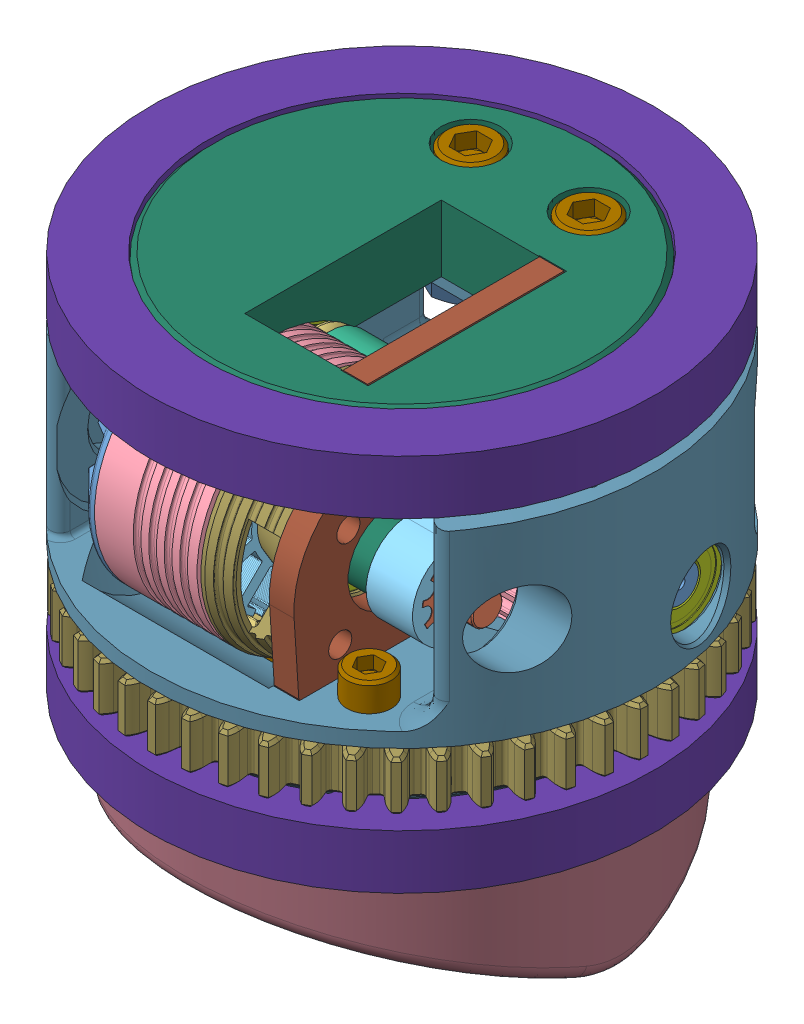
SolidWorks assembly Teathered Swerve Assem, configuration Default. Lengths in mm.
Overall size (65 79.59 67.05).
128 component instances, 35 part files, 78 mates.
Components (placement in the parent):
- Teathered Swerve Inner Structure-1: Teathered Swerve Inner Structure [Default] at origin
- BA-2310-Motor.STEP-1: BA-2310-Motor.STEP [Default] at (13.218 51.7723 56.3355) x (0 0.707107 0.707107) z (-1 0 0) size (29.1 29.1 46)
  - 2310-Rotor-Assem.STEP-1: 2310-Rotor-Assem.STEP [Default] at (14.7295 2.66 3.5453) size (29.1 29.1 46)
    - 23mm-Endbell.STEP-1: 23mm-Endbell.STEP [Default] at (-57.7218 14.2616 14.8949) size (29.1 29.1 12.75)
    - 2310-Shaft.STEP-1: 2310-Shaft.STEP [Default] at (-57.7218 14.2616 -15.3551) size (4 4 46)
    - 2310-Magnet.STEP-1: 2310-Magnet.STEP [Default] at (-57.7218 14.2616 8.6449) size (4 1.65 10)
    - 2310-Magnet.STEP-2: 2310-Magnet.STEP [Default] at (-57.7218 14.2616 8.6449) x (0.900969 0.433884 0) z (0 0 1) size (4 1.65 10)
    - 2310-Magnet.STEP-3: 2310-Magnet.STEP [Default] at (-57.7218 14.2616 8.6449) x (0.62349 0.781831 0) z (0 0 1) size (4 1.65 10)
    - 2310-Magnet.STEP-4: 2310-Magnet.STEP [Default] at (-57.7218 14.2616 8.6449) x (0.222521 0.974928 0) z (0 0 1) size (4 1.65 10)
    - 2310-Magnet.STEP-5: 2310-Magnet.STEP [Default] at (-57.7218 14.2616 8.6449) x (-0.222521 0.974928 0) z (0 0 1) size (4 1.65 10)
    - 2310-Magnet.STEP-6: 2310-Magnet.STEP [Default] at (-57.7218 14.2616 8.6449) x (-0.62349 0.781831 0) z (0 0 1) size (4 1.65 10)
    - 2310-Magnet.STEP-7: 2310-Magnet.STEP [Default] at (-57.7218 14.2616 8.6449) x (-0.900969 0.433884 0) z (0 0 1) size (4 1.65 10)
    - 2310-Magnet.STEP-8: 2310-Magnet.STEP [Default] at (-57.7218 14.2616 8.6449) x (-1 0 0) z (0 0 1) size (4 1.65 10)
    - 2310-Magnet.STEP-9: 2310-Magnet.STEP [Default] at (-57.7218 14.2616 8.6449) x (-0.900969 -0.433884 0) z (0 0 1) size (4 1.65 10)
    - 2310-Magnet.STEP-10: 2310-Magnet.STEP [Default] at (-57.7218 14.2616 8.6449) x (-0.62349 -0.781831 0) z (0 0 1) size (4 1.65 10)
    - 2310-Magnet.STEP-11: 2310-Magnet.STEP [Default] at (-57.7218 14.2616 8.6449) x (-0.222521 -0.974928 0) z (0 0 1) size (4 1.65 10)
    - 2310-Magnet.STEP-12: 2310-Magnet.STEP [Default] at (-57.7218 14.2616 8.6449) x (0.222521 -0.974928 0) z (0 0 1) size (4 1.65 10)
    - 2310-Magnet.STEP-13: 2310-Magnet.STEP [Default] at (-57.7218 14.2616 8.6449) x (0.62349 -0.781831 0) z (0 0 1) size (4 1.65 10)
    - 2310-Magnet.STEP-14: 2310-Magnet.STEP [Default] at (-57.7218 14.2616 8.6449) x (0.900969 -0.433884 0) z (0 0 1) size (4 1.65 10)
    - 2310-Fluxring.STEP-1: 2310-Fluxring.STEP [Default] at (-57.7218 14.2616 7.6449) size (29.1 29.1 13.25)
  - 2310-Stator-Assem.STEP-1: 2310-Stator-Assem.STEP [Default] at (-38.1007 -3.4232 24.6837) size (29.1 29.1 19.5)
    - 23x10x10mm-Stator.STEP-1: 23x10x10mm-Stator.STEP [Default] at (52.3253 8.3812 -27.0554) size (23 23 10)
      - 23x10x5mm-Stator.STEP-1: 23x10x5mm-Stator.STEP [Default] at (-16.2466 9.1923 4.328) size (23 23 5)
        - 23x10x1mm-Stator.STEP-1: 23x10x1mm-Stator.STEP [Default] at (-15.1244 2.7036 6.5442) size (23 23 1)
          - 23x10-Stator-Plate.STEP-1: 23x10-Stator-Plate.STEP [Default] at (-25.8459 0.0676 13.4926) size (23 23 0.2)
          - 23x10-Stator-Plate.STEP-2: 23x10-Stator-Plate.STEP [Default] at (-25.8459 0.0676 13.2926) size (23 23 0.2)
          - 23x10-Stator-Plate.STEP-3: 23x10-Stator-Plate.STEP [Default] at (-25.8459 0.0676 13.0926) size (23 23 0.2)
          - 23x10-Stator-Plate.STEP-4: 23x10-Stator-Plate.STEP [Default] at (-25.8459 0.0676 12.8926) size (23 23 0.2)
          - 23x10-Stator-Plate.STEP-5: 23x10-Stator-Plate.STEP [Default] at (-25.8459 0.0676 12.6926) size (23 23 0.2)
        - 23x10x1mm-Stator.STEP-2: 23x10x1mm-Stator.STEP [Default] at (-15.1244 2.7036 5.5442) size (23 23 1)
          - 23x10-Stator-Plate.STEP-1: 23x10-Stator-Plate.STEP [Default] at (-25.8459 0.0676 13.4926) size (23 23 0.2)
          - 23x10-Stator-Plate.STEP-2: 23x10-Stator-Plate.STEP [Default] at (-25.8459 0.0676 13.2926) size (23 23 0.2)
          - 23x10-Stator-Plate.STEP-3: 23x10-Stator-Plate.STEP [Default] at (-25.8459 0.0676 13.0926) size (23 23 0.2)
          - 23x10-Stator-Plate.STEP-4: 23x10-Stator-Plate.STEP [Default] at (-25.8459 0.0676 12.8926) size (23 23 0.2)
          - 23x10-Stator-Plate.STEP-5: 23x10-Stator-Plate.STEP [Default] at (-25.8459 0.0676 12.6926) size (23 23 0.2)
        - 23x10x1mm-Stator.STEP-3: 23x10x1mm-Stator.STEP [Default] at (-15.1244 2.7036 4.5442) size (23 23 1)
          - 23x10-Stator-Plate.STEP-1: 23x10-Stator-Plate.STEP [Default] at (-25.8459 0.0676 13.4926) size (23 23 0.2)
          - 23x10-Stator-Plate.STEP-2: 23x10-Stator-Plate.STEP [Default] at (-25.8459 0.0676 13.2926) size (23 23 0.2)
          - 23x10-Stator-Plate.STEP-3: 23x10-Stator-Plate.STEP [Default] at (-25.8459 0.0676 13.0926) size (23 23 0.2)
          - 23x10-Stator-Plate.STEP-4: 23x10-Stator-Plate.STEP [Default] at (-25.8459 0.0676 12.8926) size (23 23 0.2)
          - 23x10-Stator-Plate.STEP-5: 23x10-Stator-Plate.STEP [Default] at (-25.8459 0.0676 12.6926) size (23 23 0.2)
        - 23x10x1mm-Stator.STEP-4: 23x10x1mm-Stator.STEP [Default] at (-15.1244 2.7036 3.5442) size (23 23 1)
          - 23x10-Stator-Plate.STEP-1: 23x10-Stator-Plate.STEP [Default] at (-25.8459 0.0676 13.4926) size (23 23 0.2)
          - 23x10-Stator-Plate.STEP-2: 23x10-Stator-Plate.STEP [Default] at (-25.8459 0.0676 13.2926) size (23 23 0.2)
          - 23x10-Stator-Plate.STEP-3: 23x10-Stator-Plate.STEP [Default] at (-25.8459 0.0676 13.0926) size (23 23 0.2)
          - 23x10-Stator-Plate.STEP-4: 23x10-Stator-Plate.STEP [Default] at (-25.8459 0.0676 12.8926) size (23 23 0.2)
          - 23x10-Stator-Plate.STEP-5: 23x10-Stator-Plate.STEP [Default] at (-25.8459 0.0676 12.6926) size (23 23 0.2)
        - 23x10x1mm-Stator.STEP-5: 23x10x1mm-Stator.STEP [Default] at (-15.1244 2.7036 2.5442) size (23 23 1)
          - 23x10-Stator-Plate.STEP-1: 23x10-Stator-Plate.STEP [Default] at (-25.8459 0.0676 13.4926) size (23 23 0.2)
          - 23x10-Stator-Plate.STEP-2: 23x10-Stator-Plate.STEP [Default] at (-25.8459 0.0676 13.2926) size (23 23 0.2)
          - 23x10-Stator-Plate.STEP-3: 23x10-Stator-Plate.STEP [Default] at (-25.8459 0.0676 13.0926) size (23 23 0.2)
          - 23x10-Stator-Plate.STEP-4: 23x10-Stator-Plate.STEP [Default] at (-25.8459 0.0676 12.8926) size (23 23 0.2)
          - 23x10-Stator-Plate.STEP-5: 23x10-Stator-Plate.STEP [Default] at (-25.8459 0.0676 12.6926) size (23 23 0.2)
      - 23x10x5mm-Stator.STEP-2: 23x10x5mm-Stator.STEP [Default] at (-16.2466 9.1923 -0.672) size (23 23 5)
        - 23x10x1mm-Stator.STEP-1: 23x10x1mm-Stator.STEP [Default] at (-15.1244 2.7036 6.5442) size (23 23 1)
          - 23x10-Stator-Plate.STEP-1: 23x10-Stator-Plate.STEP [Default] at (-25.8459 0.0676 13.4926) size (23 23 0.2)
          - 23x10-Stator-Plate.STEP-2: 23x10-Stator-Plate.STEP [Default] at (-25.8459 0.0676 13.2926) size (23 23 0.2)
          - 23x10-Stator-Plate.STEP-3: 23x10-Stator-Plate.STEP [Default] at (-25.8459 0.0676 13.0926) size (23 23 0.2)
          - 23x10-Stator-Plate.STEP-4: 23x10-Stator-Plate.STEP [Default] at (-25.8459 0.0676 12.8926) size (23 23 0.2)
          - 23x10-Stator-Plate.STEP-5: 23x10-Stator-Plate.STEP [Default] at (-25.8459 0.0676 12.6926) size (23 23 0.2)
        - 23x10x1mm-Stator.STEP-2: 23x10x1mm-Stator.STEP [Default] at (-15.1244 2.7036 5.5442) size (23 23 1)
          - 23x10-Stator-Plate.STEP-1: 23x10-Stator-Plate.STEP [Default] at (-25.8459 0.0676 13.4926) size (23 23 0.2)
          - 23x10-Stator-Plate.STEP-2: 23x10-Stator-Plate.STEP [Default] at (-25.8459 0.0676 13.2926) size (23 23 0.2)
          - 23x10-Stator-Plate.STEP-3: 23x10-Stator-Plate.STEP [Default] at (-25.8459 0.0676 13.0926) size (23 23 0.2)
          - 23x10-Stator-Plate.STEP-4: 23x10-Stator-Plate.STEP [Default] at (-25.8459 0.0676 12.8926) size (23 23 0.2)
          - 23x10-Stator-Plate.STEP-5: 23x10-Stator-Plate.STEP [Default] at (-25.8459 0.0676 12.6926) size (23 23 0.2)
        - 23x10x1mm-Stator.STEP-3: 23x10x1mm-Stator.STEP [Default] at (-15.1244 2.7036 4.5442) size (23 23 1)
          - 23x10-Stator-Plate.STEP-1: 23x10-Stator-Plate.STEP [Default] at (-25.8459 0.0676 13.4926) size (23 23 0.2)
          - 23x10-Stator-Plate.STEP-2: 23x10-Stator-Plate.STEP [Default] at (-25.8459 0.0676 13.2926) size (23 23 0.2)
          - 23x10-Stator-Plate.STEP-3: 23x10-Stator-Plate.STEP [Default] at (-25.8459 0.0676 13.0926) size (23 23 0.2)
          - 23x10-Stator-Plate.STEP-4: 23x10-Stator-Plate.STEP [Default] at (-25.8459 0.0676 12.8926) size (23 23 0.2)
          - 23x10-Stator-Plate.STEP-5: 23x10-Stator-Plate.STEP [Default] at (-25.8459 0.0676 12.6926) size (23 23 0.2)
        - 23x10x1mm-Stator.STEP-4: 23x10x1mm-Stator.STEP [Default] at (-15.1244 2.7036 3.5442) size (23 23 1)
          - 23x10-Stator-Plate.STEP-1: 23x10-Stator-Plate.STEP [Default] at (-25.8459 0.0676 13.4926) size (23 23 0.2)
          - 23x10-Stator-Plate.STEP-2: 23x10-Stator-Plate.STEP [Default] at (-25.8459 0.0676 13.2926) size (23 23 0.2)
          - 23x10-Stator-Plate.STEP-3: 23x10-Stator-Plate.STEP [Default] at (-25.8459 0.0676 13.0926) size (23 23 0.2)
          - 23x10-Stator-Plate.STEP-4: 23x10-Stator-Plate.STEP [Default] at (-25.8459 0.0676 12.8926) size (23 23 0.2)
          - 23x10-Stator-Plate.STEP-5: 23x10-Stator-Plate.STEP [Default] at (-25.8459 0.0676 12.6926) size (23 23 0.2)
        - 23x10x1mm-Stator.STEP-5: 23x10x1mm-Stator.STEP [Default] at (-15.1244 2.7036 2.5442) size (23 23 1)
          - 23x10-Stator-Plate.STEP-1: 23x10-Stator-Plate.STEP [Default] at (-25.8459 0.0676 13.4926) size (23 23 0.2)
          - 23x10-Stator-Plate.STEP-2: 23x10-Stator-Plate.STEP [Default] at (-25.8459 0.0676 13.2926) size (23 23 0.2)
          - 23x10-Stator-Plate.STEP-3: 23x10-Stator-Plate.STEP [Default] at (-25.8459 0.0676 13.0926) size (23 23 0.2)
          - 23x10-Stator-Plate.STEP-4: 23x10-Stator-Plate.STEP [Default] at (-25.8459 0.0676 12.8926) size (23 23 0.2)
          - 23x10-Stator-Plate.STEP-5: 23x10-Stator-Plate.STEP [Default] at (-25.8459 0.0676 12.6926) size (23 23 0.2)
    - 4x11x4-BRG.STEP-1: 4x11x4-BRG.STEP [Default] at (-4.8916 20.3447 -18.4846) x (0 0 1) z (-0.998854 -0.047866 0) size (3.99 11 11)
      - 694HZZ_SOLID_1-1.STEP-1: 694HZZ_SOLID_1-1.STEP [Default] at origin size (3.99 6.18 6.18)
      - 694HZZ_SOLID_2-1.STEP-1: 694HZZ_SOLID_2-1.STEP [Default] at origin size (3.99 11 11)
      - 694HZZ_SOLID_3-1.STEP-1: 694HZZ_SOLID_3-1.STEP [Default] at origin size (2.34 9.37 9.37)
    - 4x8x3-BRG.STEP-1: 4x8x3-BRG.STEP [Default] at (-4.8916 20.3447 -2.9921) x (0 0 -1) z (0.838857 -0.544351 0) size (3 8 8)
      - SMR84ZZ_SOLID_1.STEP-1: SMR84ZZ_SOLID_1.STEP [Default] at origin size (3 5.01 5.01)
      - SMR84ZZ_SOLID_2.STEP-1: SMR84ZZ_SOLID_2.STEP [Default] at origin size (3 8 8)
      - SMR84ZZ_SOLID_3.STEP-1: SMR84ZZ_SOLID_3.STEP [Default] at origin size (1.76 7.4 7.4)
    - 2310-Mount.STEP-1: 2310-Mount.STEP [Default] at (-4.8916 20.3447 -20.9907) size (29.1 29.1 19.5)
  - Spacer-4mm.STEP-1: Spacer-4mm.STEP [Default] at (-42.9923 16.9215 23.1902) size (6 6 0.25)
  - Spacer-4mm.STEP-2: Spacer-4mm.STEP [Default] at (-42.9923 16.9215 3.9552) size (6 6 0.25)
  - C-Clip-4mm_98541A112.STEP-1: C-Clip-4mm_98541A112.STEP [Default] at (-42.9923 16.9215 3.7402) x (0 0 -1) z (0.963178 -0.268866 0) size (0.4 6.8 5.16)
  - Collar-4mm.STEP-1: Collar-4mm.STEP [Default] at (-42.9923 16.9215 -1.4598) x (0 1 0) z (0 0 1) size (8.5 8.5 5)
  - M2.5x3-SetScrew.STEP-1: M2.5x3-SetScrew.STEP [Default] at (-42.9923 20.0215 0.7902) x (0.871933 0 -0.489626) z (0 1 0) size (2.89 2.5 3.01)
- Zoro Bearing 50mmID 65mm OD 7mmWidth-1: Zoro Bearing 50mmID 65mm OD 7mmWidth [Default] at (0 50.475 0) size (65 7 65)
- Zoro Bearing 50mmID 65mm OD 7mmWidth-2: Zoro Bearing 50mmID 65mm OD 7mmWidth [Default] at (0 8.55 0) size (65 7 65)
- Wheel with Pully-1: Wheel with Pully [Default] x (0 -0.449614 0.893223) z (0 -0.893223 -0.449614) size (38.1 24.77 38.1)
- Inner Modual Intermediate Shaft-1: Inner Modual Intermediate Shaft [Default] at (1.7272 27.4182 -7.2941) x (0 -0.995575 -0.093965) z (0 -0.093965 0.995575) size (5.5 53.85 4.76)
- Drive Stage 1 Pinion-1: Drive Stage 1 Pinion [Aluminum Version] at (17.8528 33.3375 13.97) x (0 0.98945 0.144875) z (0 0.144875 -0.98945) size (8.79 6.35 8.54)
- Drive Stage 2 Pinion-1: Drive Stage 2 Pinion [Default] at (-12.1285 27.4182 -7.2941) x (0 -0.995575 -0.093965) z (0 -0.093965 0.995575) size (10.57 36.37 10.57)
- Drive Stage 1 Pully-1: Drive Stage 1 Pully [Default] at (17.9578 27.4182 -7.2941) x (0 -0.995575 -0.093965) z (0 -0.093965 0.995575) size (24.89 10.48 24.89)
- Drive Stage 1 Belt-1: Drive Stage 1 Belt [Default] at (17.9578 33.3375 13.97) x (1 0 0) z (0 0.268176 0.96337) size (6 27.13 41.27)
- Drive Stage 2 Belt-1: Drive Stage 2 Belt [Default] at (-12.1285 27.4182 -7.2941) x (1 0 0) z (0 0.966388 -0.257089) size (9 31.9 49.96)
- 60355K861_Ball Bearing-1: 60355K861_Ball Bearing [60355K861] at (26.162 27.4182 -7.2941) x (0 0 -1) z (1 0 0) size (12.7 12.7 4.98)
- 60355K861_Ball Bearing-2: 60355K861_Ball Bearing [60355K861] at (-22.7838 27.4182 -7.2941) x (0 0.531717 -0.846922) z (1 0 0) size (12.7 12.7 4.98)
- Wheel Shaft-1: Wheel Shaft [Default] x (0 0 1) z (1 0 0) size (9.53 10.25 47.62)
- socket head cap screw_ai-4: socket head cap screw_ai [HX-SHCS 0.164-32x0.375x0.375-N] at (23.2156 17.13 10.795) x (-1 0 0) z (0 0.924225 0.381849) size (13.69 6.86 6.86)
- socket head cap screw_ai-7: socket head cap screw_ai [HX-SHCS 0.164-32x0.375x0.375-N] at (23.2156 49.53 5.715) x (-1 0 0) z (0 0.924225 0.381849) size (13.69 6.86 6.86)
- socket head cap screw_ai-8: socket head cap screw_ai [HX-SHCS 0.164-32x0.375x0.375-N] at (23.2156 49.53 -1.905) x (-1 0 0) z (0 0.924225 0.381849) size (13.69 6.86 6.86)
- socket head cap screw_ai-10: socket head cap screw_ai [HX-SHCS 0.138-32x0.375x0.375-N] at (16.8402 26.6677 21.0887) x (0 -1 0) z (0 0 1) size (13.03 5.74 5.74)
- socket head cap screw_ai-11: socket head cap screw_ai [HX-SHCS 0.138-32x0.375x0.375-N] at (8.255 26.6677 -25.694) x (0 -1 0) z (0 0 1) size (13.03 5.74 5.74)
- socket head cap screw_ai-12: socket head cap screw_ai [HX-SHCS 0.138-32x0.375x0.375-N] at (-15.24 26.6677 -22.2726) x (0 -1 0) z (0 0 1) size (13.03 5.74 5.74)
- socket head cap screw_ai-13: socket head cap screw_ai [HX-SHCS 0.138-32x0.375x0.375-N] at (-26.2298 26.6677 6.35) x (0 -1 0) z (0 0 1) size (13.03 5.74 5.74)
- machine screw nut hex_ai-6: machine screw nut hex_ai [MSHXNUT 0.164-32-S-N] at (-7.62 38.9105 -16.51) x (1 0 0) z (0 -1 0) size (8.74 10.09 3.3)
- machine screw nut hex_ai-7: machine screw nut hex_ai [MSHXNUT 0.164-32-S-N] at (7.62 38.9105 -16.51) x (1 0 0) z (0 -1 0) size (8.74 10.09 3.3)
- socket head cap screw_ai-16: socket head cap screw_ai [HX-SHCS 0.164-32x0.5x0.5-N] at (7.62 53.975 -16.51) x (0 -1 0) z (0 0 1) size (16.87 6.86 6.86)
- socket head cap screw_ai-17: socket head cap screw_ai [HX-SHCS 0.164-32x0.5x0.5-N] at (-7.62 53.975 -16.51) x (0 -1 0) z (0 0 1) size (16.87 6.86 6.86)
- Drive Motor Mount-1: Drive Motor Mount [Default] at origin size (3.17 41.93 34.92)
- Final Steer Gear-1: Final Steer Gear [Default] at origin size (64.76 6.35 64.73)
- Inner Structure Bottom-1: Inner Structure Bottom [Default] at origin size (56.35 17.75 56.35)
- Inner Structure Mid-1: Inner Structure Mid [Default] at origin size (65 46.99 65)
- Inner Structure Top-1: Inner Structure Top [Default] at origin size (56.52 8.59 56.35)
- .375 Thunder Hex Bearing-2: .375 Thunder Hex Bearing [Default] at (-18.4023 0 0) x (1 0 0) z (0 -0.11391 0.993491) size (7.11 24.61 24.61)
- .375 Thunder Hex Bearing-3: .375 Thunder Hex Bearing [Default] at (6.3373 0 0) x (-1 0 0) z (0 -0.999894 -0.014533) size (7.11 24.61 24.61)
Mates (geometry in assembly coordinates):
- Coincident1: coincident aligned: plane of Teathered Swerve Inner Structure-1 through (0 0 0) normal (0 0 1)
- Coincident2: coincident aligned: plane of Teathered Swerve Inner Structure-1 through (0 0 0) normal (0 1 0)
- Coincident3: coincident aligned: plane of Teathered Swerve Inner Structure-1 through (0 0 0) normal (1 0 0)
- Concentric1: concentric aligned: circle of Teathered Swerve Sketch-1; cylinder of BA-2310-Motor.STEP-1/2310-Rotor-Assem.STEP-1/2310-Shaft.STEP-1 through (-20.9722 33.3375 13.97) axis (1 0 0) radius 2
- Coincident4: coincident: line of Teathered Swerve Inner Structure-1 through (9.525 0 28.5242) axis (0 0 -1); plane of BA-2310-Motor.STEP-1/2310-Stator-Assem.STEP-1/2310-Mount.STEP-1 through (9.525 33.3375 13.97) normal (1 0 0)
- Coincident5: coincident anti-aligned: circle of Teathered Swerve Sketch-1; cylinder of Zoro Bearing 50mmID 65mm OD 7mmWidth-2 through (0 12.05 0) axis (0 -1 0) radius 25
- Concentric2: concentric aligned: cylinder of Zoro Bearing 50mmID 65mm OD 7mmWidth-1 through (0 53.975 0) axis (0 -1 0) radius 25; cylinder of Zoro Bearing 50mmID 65mm OD 7mmWidth-2 through (0 12.05 0) axis (0 -1 0) radius 25
- Coincident6: coincident: line of Teathered Swerve Inner Structure-1 through (0 53.975 -32.5) axis (0 0 1); plane of Zoro Bearing 50mmID 65mm OD 7mmWidth-1 through (0 53.975 0) normal (0 1 0)
- Coincident7: coincident: line of Teathered Swerve Inner Structure-1 through (0 5.05 -32.5) axis (0 0 1); plane of Zoro Bearing 50mmID 65mm OD 7mmWidth-2 through (0 5.05 0) normal (0 -1 0)
- Coincident8: coincident anti-aligned: plane of Wheel with Pully-1 through (0 0 0) normal (-1 0 0)
- Coincident9: coincident anti-aligned: circle of Teathered Swerve Sketch-1; cylinder of Wheel with Pully-1 through (6.35 0 0) axis (-1 0 0) radius 19.05
- Concentric3: concentric anti-aligned: circle of Teathered Swerve Sketch-1; cylinder of Inner Modual Intermediate Shaft-1 through (23.6728 27.4182 -7.2941) axis (-1 0 0) radius 0.635
- Concentric4: concentric anti-aligned: cylinder of BA-2310-Motor.STEP-1/2310-Rotor-Assem.STEP-1/2310-Shaft.STEP-1 through (-20.9722 33.3375 13.97) axis (1 0 0) radius 2; cylinder of Drive Stage 1 Pinion-1 through (22.3613 33.3375 13.97) axis (-1 0 0) radius 2
- Concentric5: concentric anti-aligned: cylinder of Inner Modual Intermediate Shaft-1 through (23.6728 27.4182 -7.2941) axis (-1 0 0) radius 0.635; cylinder of Drive Stage 2 Pinion-1 through (-3.3973 27.4182 -7.2941) axis (1 0 0) radius 5.2826
- Coincident12: coincident aligned: plane of Wheel with Pully-1 through (-17.4625 0 0) normal (1 0 0); plane of Drive Stage 2 Pinion-1 through (-17.4625 27.4182 -7.2941) normal (1 0 0)
- Concentric6: concentric aligned: cylinder of Inner Modual Intermediate Shaft-1 through (23.6728 27.4182 -7.2941) axis (-1 0 0) radius 0.635; cylinder of Drive Stage 1 Pully-1 through (23.6728 27.4182 -7.2941) axis (-1 0 0) radius 3.81
- Width1: width anti-aligned: plane of Drive Stage 1 Belt-1 through (14.9578 33.3375 13.97) normal (-1 0 0); plane of Drive Stage 1 Pully-1 through (20.9578 33.3375 13.97) normal (1 0 0); plane of Drive Stage 1 Belt-1 through (14.4653 27.4182 -7.2941) normal (1 0 0); plane of Drive Stage 1 Pully-1 through (21.4503 27.4182 -7.2941) normal (-1 0 0)
- Concentric7: concentric anti-aligned: cylinder of BA-2310-Motor.STEP-1/2310-Rotor-Assem.STEP-1/2310-Shaft.STEP-1 through (-20.9722 33.3375 13.97) axis (1 0 0) radius 2; cylinder of Drive Stage 1 Belt-1 through (20.9578 33.3375 13.97) axis (-1 0 0) radius 2.4638
- Concentric8: concentric aligned: cylinder of Drive Stage 1 Pully-1 through (23.6728 27.4182 -7.2941) axis (-1 0 0) radius 3.81; cylinder of Drive Stage 1 Belt-1 through (20.9578 27.4182 -7.2941) axis (-1 0 0) radius 10.3886
- Width2: width anti-aligned: plane of Drive Stage 2 Belt-1 through (-16.6285 27.4182 -7.2941) normal (-1 0 0); plane of Drive Stage 2 Pinion-1 through (-7.6285 27.4182 -7.2941) normal (1 0 0); plane of Drive Stage 2 Belt-1 through (-17.4625 27.4182 -7.2941) normal (1 0 0); plane of Drive Stage 2 Pinion-1 through (-6.7945 27.4182 -7.2941) normal (-1 0 0)
- Concentric9: concentric aligned: cylinder of Inner Modual Intermediate Shaft-1 through (23.6728 27.4182 -7.2941) axis (-1 0 0) radius 0.635; cylinder of Drive Stage 2 Belt-1 through (-7.6285 27.4182 -7.2941) axis (-1 0 0) radius 2.4638
- Concentric10: concentric aligned: cylinder of Wheel with Pully-1 through (-21.1137 0 0) axis (-1 0 0) radius 15.7209; cylinder of Drive Stage 2 Belt-1 through (-7.6285 0 0) axis (-1 0 0) radius 12.7762
- Coincident14: coincident aligned: plane of Inner Modual Intermediate Shaft-1 through (23.6728 27.4182 -7.2941) normal (1 0 0); plane of Drive Stage 1 Pully-1 through (23.6728 27.4182 -7.2941) normal (1 0 0)
- Parallel1: parallel anti-aligned: plane of Inner Modual Intermediate Shaft-1 through (23.6728 29.0106 -9.5356) normal (0 0.909176 -0.416411); plane of Drive Stage 1 Pully-1 through (22.7203 30.1994 -7.0316) normal (0 -0.909176 0.416411)
- Parallel2: parallel anti-aligned: plane of Inner Modual Intermediate Shaft-1 through (23.6728 30.1556 -7.0357) normal (0 0.815211 0.579164); plane of Drive Stage 2 Pinion-1 through (-5.7785 28.5815 -4.7542) normal (0 -0.815211 -0.579164)
- GearMate1: gear = 63.5 : 25.4 mm: circle of Drive Stage 1 Pinion-1; cylinder of Drive Stage 1 Pully-1 through (23.6728 27.4182 -7.2941) axis (-1 0 0) radius 3.81
- GearMate2: gear = 31.4419 : 25.4 mm: circle of Drive Stage 2 Pinion-1; cylinder of Wheel with Pully-1 through (-21.1137 0 0) axis (-1 0 0) radius 15.7209
- Concentric11: concentric anti-aligned: cylinder of Inner Modual Intermediate Shaft-1 through (28.6512 27.4182 -7.2941) axis (-1 0 0) radius 2.3813; cylinder of 60355K861_Ball Bearing-1 through (28.6512 27.4182 -7.2941) axis (1 0 0) radius 2.3813
- Coincident17: coincident anti-aligned: plane of Drive Stage 1 Pully-1 through (23.6728 27.4182 -7.2941) normal (1 0 0); plane of 60355K861_Ball Bearing-1 through (23.6728 30.0483 -7.2941) normal (-1 0 0)
- Concentric12: concentric aligned: cylinder of Inner Modual Intermediate Shaft-1 through (-25.1968 27.4182 -7.2941) axis (1 0 0) radius 2.3813; cylinder of 60355K861_Ball Bearing-2 through (-20.2946 27.4182 -7.2941) axis (1 0 0) radius 2.3813
- Coincident18: coincident aligned: plane of 60355K861_Ball Bearing-2 through (-25.273 32.5853 -4.05) normal (-1 0 0); plane of Inner Structure Mid-1 through (-25.273 27.4182 -7.2941) normal (-1 0 0)
- Coincident21: coincident aligned: plane of Wheel Shaft-1 through (0 0 0) normal (1 0 0)
- Parallel3: parallel anti-aligned: plane of Wheel Shaft-1 through (23.8125 3.1786 -4.0195) normal (0 0.866025 -0.5); plane of Inner Structure Mid-1 through (-23.8125 2.9329 -5.08) normal (0 -0.866025 0.5)
- Concentric17: concentric anti-aligned: cylinder of Inner Structure Mid-1 through (32.5 17.13 10.795) axis (-1 0 0) radius 2.2479; cylinder of socket head cap screw_ai-4 through (54.9656 17.13 10.795) axis (1 0 0) radius 3.429
- Coincident23: coincident anti-aligned: plane of Inner Structure Mid-1 through (19.05 17.13 10.795) normal (1 0 0); plane of socket head cap screw_ai-4 through (19.05 15.8206 13.9642) normal (-1 0 0)
- Concentric18: concentric anti-aligned: cylinder of Inner Structure Top-1 through (32.5 49.53 5.715) axis (-1 0 0) radius 2.2479; cylinder of socket head cap screw_ai-7 through (54.9656 49.53 5.715) axis (1 0 0) radius 3.429
- Coincident24: coincident anti-aligned: plane of Inner Structure Top-1 through (19.05 49.53 5.715) normal (1 0 0); plane of socket head cap screw_ai-7 through (19.05 48.2206 8.8842) normal (-1 0 0)
- Concentric19: concentric anti-aligned: cylinder of Inner Structure Top-1 through (32.5 49.53 -1.905) axis (-1 0 0) radius 2.2479; cylinder of socket head cap screw_ai-8 through (54.9656 49.53 -1.905) axis (1 0 0) radius 3.429
- Coincident25: coincident anti-aligned: plane of Inner Structure Top-1 through (19.05 49.53 -1.905) normal (1 0 0); plane of socket head cap screw_ai-8 through (19.05 48.2206 1.2642) normal (-1 0 0)
- Concentric20: concentric anti-aligned: cylinder of Drive Motor Mount-1 through (32.501 38.9944 19.6269) axis (-1 0 0) radius 1.5; cylinder of BA-2310-Motor.STEP-1/2310-Stator-Assem.STEP-1/2310-Mount.STEP-1 through (9.525 38.9944 19.6269) axis (1 0 0) radius 1.25
- Concentric21: concentric anti-aligned: cylinder of Inner Structure Mid-1 through (16.8402 53.975 21.0887) axis (0 -1 0) radius 1.7526; cylinder of socket head cap screw_ai-10 through (16.8402 58.4177 21.0887) axis (0 1 0) radius 2.8702
- Coincident26: coincident anti-aligned: plane of Inner Structure Mid-1 through (0 23.1625 0) normal (0 1 0); plane of socket head cap screw_ai-10 through (19.7104 23.1625 21.0887) normal (0 -1 0)
- Concentric22: concentric anti-aligned: cylinder of Inner Structure Mid-1 through (8.255 53.975 -25.694) axis (0 -1 0) radius 1.7526; cylinder of socket head cap screw_ai-11 through (8.255 58.4177 -25.694) axis (0 1 0) radius 2.8702
- Coincident27: coincident anti-aligned: plane of Inner Structure Mid-1 through (0 23.1625 0) normal (0 1 0); plane of socket head cap screw_ai-11 through (11.1252 23.1625 -25.694) normal (0 -1 0)
- Concentric23: concentric anti-aligned: cylinder of Inner Structure Mid-1 through (-15.24 53.975 -22.2726) axis (0 -1 0) radius 1.7526; cylinder of socket head cap screw_ai-12 through (-15.24 58.4177 -22.2726) axis (0 1 0) radius 2.8702
- Coincident28: coincident anti-aligned: plane of Inner Structure Mid-1 through (0 23.1625 0) normal (0 1 0); plane of socket head cap screw_ai-12 through (-12.3698 23.1625 -22.2726) normal (0 -1 0)
- Concentric24: concentric anti-aligned: cylinder of Inner Structure Mid-1 through (-26.2298 53.975 6.35) axis (0 -1 0) radius 1.7526; cylinder of socket head cap screw_ai-13 through (-26.2298 58.4177 6.35) axis (0 1 0) radius 2.8702
- Coincident29: coincident anti-aligned: plane of Inner Structure Mid-1 through (-26.2298 23.1625 6.35) normal (0 1 0); plane of socket head cap screw_ai-13 through (-23.3596 23.1625 6.35) normal (0 -1 0)
- Concentric29: concentric anti-aligned: cylinder of Inner Structure Mid-1 through (-7.62 35.8545 -16.51) axis (0 1 0) radius 2.2479; cylinder of machine screw nut hex_ai-6 through (-7.62 63.948 -16.51) axis (0 -1 0) radius 2.0828
- Coincident33: coincident anti-aligned: plane of Inner Structure Mid-1 through (-18.8486 42.2125 13.0053) normal (0 -1 0); plane of machine screw nut hex_ai-6 through (-16.3576 42.2125 -16.51) normal (0 1 0)
- Concentric30: concentric anti-aligned: cylinder of Inner Structure Mid-1 through (7.62 35.8545 -16.51) axis (0 1 0) radius 2.2479; cylinder of machine screw nut hex_ai-7 through (7.62 63.948 -16.51) axis (0 -1 0) radius 2.0828
- Coincident34: coincident anti-aligned: plane of Inner Structure Mid-1 through (-18.8486 42.2125 13.0053) normal (0 -1 0); plane of machine screw nut hex_ai-7 through (-1.1176 42.2125 -16.51) normal (0 1 0)
- Concentric31: concentric aligned: cylinder of Inner Structure Top-1 through (7.62 35.8545 -16.51) axis (0 1 0) radius 2.2479; cylinder of socket head cap screw_ai-16 through (7.62 85.725 -16.51) axis (0 1 0) radius 3.429
- Coincident35: coincident anti-aligned: plane of Inner Structure Top-1 through (7.62 49.8094 -16.51) normal (0 1 0); plane of socket head cap screw_ai-16 through (11.049 49.8094 -16.51) normal (0 -1 0)
- Concentric32: concentric aligned: cylinder of Inner Structure Top-1 through (-7.62 35.8545 -16.51) axis (0 1 0) radius 2.2479; cylinder of socket head cap screw_ai-17 through (-7.62 85.725 -16.51) axis (0 1 0) radius 3.429
- Coincident36: coincident anti-aligned: plane of Inner Structure Top-1 through (-7.62 49.8094 -16.51) normal (0 1 0); plane of socket head cap screw_ai-17 through (-4.191 49.8094 -16.51) normal (0 -1 0)
- Coincident39: coincident aligned: plane of Drive Motor Mount-1 through (0 0 0) normal (0 0 1)
- Coincident40: coincident aligned: plane of Drive Motor Mount-1 through (0 0 0) normal (0 1 0)
- Coincident41: coincident aligned: plane of Drive Motor Mount-1 through (0 0 0) normal (1 0 0)
- Coincident42: coincident aligned: plane of Final Steer Gear-1 through (0 0 0) normal (0 0 1)
- Coincident43: coincident aligned: plane of Final Steer Gear-1 through (0 0 0) normal (0 1 0)
- Coincident44: coincident aligned: plane of Final Steer Gear-1 through (0 0 0) normal (1 0 0)
- Coincident45: coincident aligned: plane of Inner Structure Bottom-1 through (0 0 0) normal (0 0 1)
- Coincident46: coincident aligned: plane of Inner Structure Bottom-1 through (0 0 0) normal (0 1 0)
- Coincident47: coincident aligned: plane of Inner Structure Bottom-1 through (0 0 0) normal (1 0 0)
- Coincident48: coincident aligned: plane of Inner Structure Mid-1 through (0 0 0) normal (0 0 1)
- Coincident49: coincident aligned: plane of Inner Structure Mid-1 through (0 0 0) normal (0 1 0)
- Coincident50: coincident aligned: plane of Inner Structure Mid-1 through (0 0 0) normal (1 0 0)
- Coincident51: coincident aligned: plane of Inner Structure Top-1 through (0 0 0) normal (0 0 1)
- Coincident52: coincident aligned: plane of Inner Structure Top-1 through (0 0 0) normal (0 1 0)
- Coincident53: coincident aligned: plane of Inner Structure Top-1 through (0 0 0) normal (1 0 0)
- Coincident54: coincident anti-aligned: plane of 60355K861_Ball Bearing-1 through (28.6512 33.5192 -7.2941) normal (1 0 0); plane of Inner Structure Mid-1 through (28.6512 27.4182 -7.2941) normal (-1 0 0)
- Coincident55: coincident anti-aligned: plane of BA-2310-Motor.STEP-1/Collar-4mm.STEP-1 through (14.6778 33.3375 13.97) normal (1 0 0); plane of Drive Stage 1 Pinion-1 through (14.6778 33.3375 13.97) normal (-1 0 0)
- Concentric34: concentric anti-aligned: cylinder of Wheel with Pully-1 through (-18.415 0 0) axis (1 0 0) radius 11.1125; cylinder of .375 Thunder Hex Bearing-2 through (-11.2903 0 0) axis (-1 0 0) radius 11.1125
- Coincident56: coincident anti-aligned: plane of Wheel with Pully-1 through (-16.8148 0 0) normal (-1 0 0); plane of .375 Thunder Hex Bearing-2 through (-16.8148 12.2262 1.4018) normal (1 0 0)
- Concentric35: concentric aligned: cylinder of Wheel with Pully-1 through (-18.415 0 0) axis (1 0 0) radius 11.1125; cylinder of .375 Thunder Hex Bearing-3 through (-0.7747 0 0) axis (1 0 0) radius 11.1125
- Coincident57: coincident anti-aligned: plane of Wheel with Pully-1 through (4.7498 0 0) normal (1 0 0); plane of .375 Thunder Hex Bearing-3 through (4.7498 0.1789 -12.305) normal (-1 0 0)
- Concentric36: concentric anti-aligned: cylinder of Wheel with Pully-1 through (6.35 0 0) axis (-1 0 0) radius 19.05; cylinder of Wheel Shaft-1 through (-23.8125 0 0) axis (1 0 0) radius 2.5527
